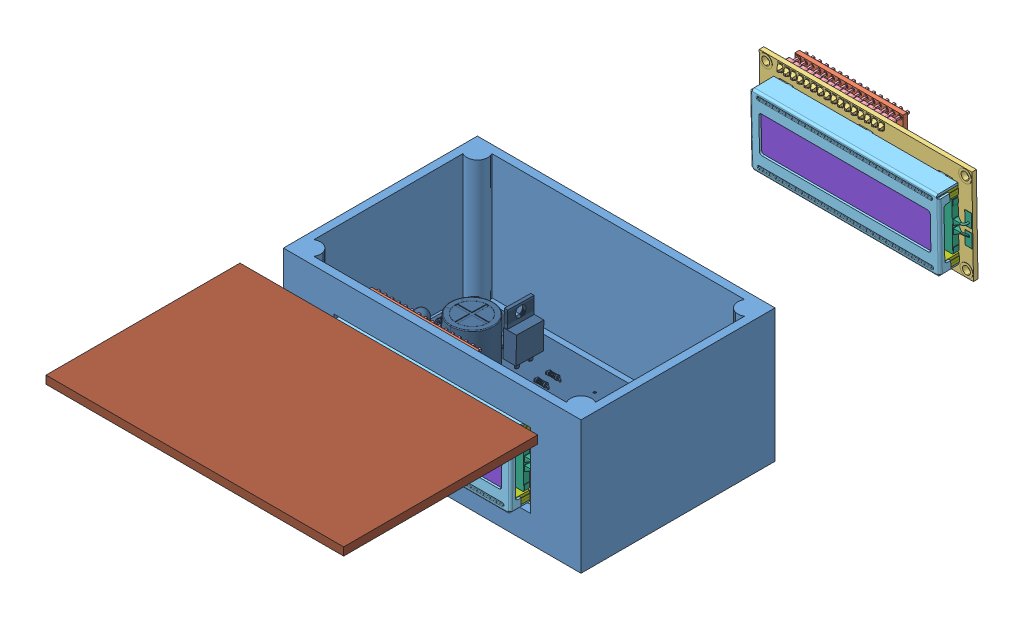
SolidWorks assembly Assem1, configuration Default. Lengths in mm.
Overall size (112.07 53.2 263.06).
37 component instances, 12 part files, 0 mates.
Components (placement in the parent):
- Eclosure-1: Eclosure [Default] at (-4.6005 54.4825 99.5642) size (112 50 73)
- LCD AP214.STEP-1: LCD AP214.STEP [Default] at (-4.5223 77.8044 -28.9185) x (1 0 0) z (0 -0.999848 -0.017452) size (80 18.3 36)
  - i2c board.STEP-1: i2c board.STEP [Default] at (6.1 -5 -15.5) x (-1 0 0) z (0 0 1) size (40.64 1.8 19.35)
  - pcbboard.STEP-1: pcbboard.STEP [Default] at origin size (80 4.19 36)
  - 16pin_header__.STEP-1: 16pin_header__.STEP [Default] at (-32 0 -15.5) x (0 0 1) z (1 0 0) size (2.54 11.5 40.64)
  - lcd window.STEP-1: lcd window.STEP [Default] at (0 9 1.5) size (71.3 11.8 27.44)
  - backlight.STEP-1: backlight.STEP [Default] at (0 1.7 1.5) x (-1 0 0) z (0 0 -1) size (74.38 2.98 18)
  - conductor.STEP-1: conductor.STEP [Default] at (0 1.7 12.6) size (69.7 5.5 3)
  - conductor.STEP-2: conductor.STEP [Default] at (0 1.7 -9.6) size (69.7 5.5 3)
  - liquid crystal grabcad i2s.STEP-1: liquid crystal grabcad i2s.STEP [Default] at (0 7.9 1.5) size (68.5 2.2 25)
  - smt_resistor222.x_t-1: smt_resistor222.x_t [Default] at (-32.75 0 -5.25) x (0 0 1) z (1 0 0)
  - smt_resistor222.x_t-2: smt_resistor222.x_t [Default] at (-32.75 0 -2.75) x (0 0 1) z (1 0 0)
  - smt_resistor222.x_t-3: smt_resistor222.x_t [Default] at (-32.75 0 -0.25) x (0 0 1) z (1 0 0)
  - smt_resistor222.x_t-4: smt_resistor222.x_t [Default] at (-32.75 0 2.25) x (0 0 1) z (1 0 0)
  - smt_resistor222.x_t-5: smt_resistor222.x_t [Default] at (-32.75 0 4.75) x (0 0 1) z (1 0 0)
  - smt_resistor222.x_t-6: smt_resistor222.x_t [Default] at (-32.75 0 7.25) x (0 0 1) z (1 0 0)
  - smt_resistor101.STEP-1: smt_resistor101.STEP [Default] at (30.25 0 6.1) x (0 0 -1) z (-1 0 0) size (1.8 0.6 5.2)
  - smt_resistor101.STEP-2: smt_resistor101.STEP [Default] at (30.25 0 2.85) x (0 0 -1) z (-1 0 0) size (1.8 0.6 5.2)
- LCD - AP203.STEP-2: LCD - AP203.STEP [Default] at (-5.6436 80.0384 131.3014) x (1 0 0) z (0 -0.999962 0.008727) size (80 18.3 36)
  - i2c board.STEP-1: i2c board.STEP [Default] at (6.1 -5 -15.5) x (-1 0 0) z (0 0 1) size (40.64 1.8 19.35)
  - pcbboard.STEP-1: pcbboard.STEP [Default] at origin size (80 4.19 36)
  - 16pin_header__.STEP-1: 16pin_header__.STEP [Default] at (-32 0 -15.5) x (0 0 1) z (1 0 0) size (2.54 11.5 40.64)
  - lcd window.STEP-1: lcd window.STEP [Default] at (0 9 1.5) size (71.3 11.8 27.44)
  - backlight.STEP-1: backlight.STEP [Default] at (0 1.7 1.5) x (-1 0 0) z (0 0 -1) size (74.38 2.98 18)
  - conductor.STEP-1: conductor.STEP [Default] at (0 1.7 12.6) size (69.7 5.5 3)
  - conductor.STEP-2: conductor.STEP [Default] at (0 1.7 -9.6) size (69.7 5.5 3)
  - liquid crystal grabcad i2s.STEP-1: liquid crystal grabcad i2s.STEP [Default] at (0 7.9 1.5) size (68.5 2.2 25)
  - smt_resistor222.x_t-1: smt_resistor222.x_t [Default] at (-32.75 0 -5.25) x (0 0 1) z (1 0 0)
  - smt_resistor222.x_t-2: smt_resistor222.x_t [Default] at (-32.75 0 -2.75) x (0 0 1) z (1 0 0)
  - smt_resistor222.x_t-3: smt_resistor222.x_t [Default] at (-32.75 0 -0.25) x (0 0 1) z (1 0 0)
  - smt_resistor222.x_t-4: smt_resistor222.x_t [Default] at (-32.75 0 2.25) x (0 0 1) z (1 0 0)
  - smt_resistor222.x_t-5: smt_resistor222.x_t [Default] at (-32.75 0 4.75) x (0 0 1) z (1 0 0)
  - smt_resistor222.x_t-6: smt_resistor222.x_t [Default] at (-32.75 0 7.25) x (0 0 1) z (1 0 0)
  - smt_resistor101.STEP-1: smt_resistor101.STEP [Default] at (30.25 0 6.1) x (0 0 -1) z (-1 0 0) size (1.8 0.6 5.2)
  - smt_resistor101.STEP-2: smt_resistor101.STEP [Default] at (30.25 0 2.85) x (0 0 -1) z (-1 0 0) size (1.8 0.6 5.2)
- PCB1-1: PCB1 [Default] at (-84.2083 62.8721 198.332) x (1 0 0) z (0 0.999848 -0.017452) size (103.49 128.7 35)
- lid-1: lid [Default] at (-4.669 104.6794 188.8245) size (112 3 73)
